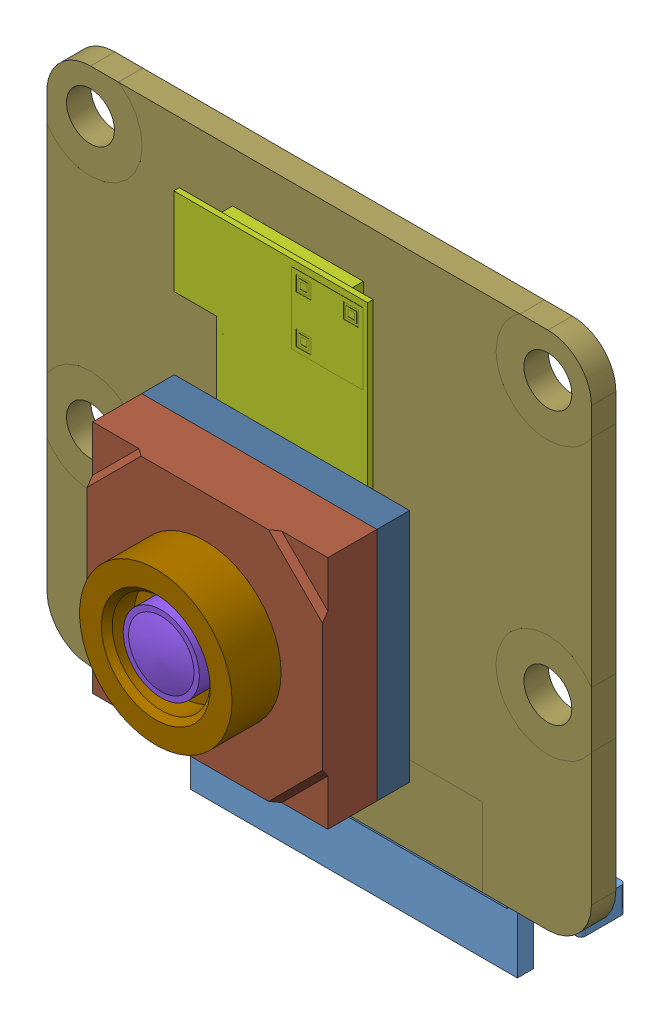
SolidWorks assembly AV_Comp_Mech_1_3_1_6_Pi_Cam, configuration Default. Lengths in mm.
Overall size (25 28.06 11.35).
16 component instances, 13 part files, 0 mates.
Components (placement in the parent):
- AV_Comp_Mech_1_3_1_6_Pi_Cam.step-1: AV_Comp_Mech_1_3_1_6_Pi_Cam.step [Default] at origin size (25 28.06 11.35)
  - Rear Components.step-1: Rear Components.step [Default] at origin size (20.8 26.49 2.7)
    - sfw15r3ste1lf.step-1: sfw15r3ste1lf.step [Default] at (-17.3 -10.562 -4.82) x (1 0 0) z (0 -1 0) size (20.8 2.7 9.5)
    - Rear Components-0.step-1: Rear Components-0.step [Default] at origin size (3 1.5 1)
    - Rear Components-1.step-1: Rear Components-1.step [Default] at origin size (5 3 1)
    - Rear Components-2.step-1: Rear Components-2.step [Default] at origin size (3 1.5 1)
    - Rear Components-3.step-1: Rear Components-3.step [Default] at origin size (3 1.5 1)
    - Rear Components-4.step-1: Rear Components-4.step [Default] at origin size (2 3 1)
  - Sony IMX708.step-1: Sony IMX708.step [Default] at origin size (10.83 18.1 7.53)
    - Sensor.step-1: Sensor.step [Default] at origin size (8.9 16.17 1.26)
    - Lens.step-1: Lens.step [Default] at origin size (3.5 3.5 6.28)
    - Ring.step-1: Ring.step [Default] at origin size (7 7 6.25)
    - Mount.step-1: Mount.step [Default] at origin size (10.8 10.8 1.5)
    - Housing.step-1: Housing.step [Default] at origin size (10.8 10.8 2.5)
  - Board.step-1: Board.step [Default] at origin size (25 23.86 1.12)
  - Camera Moudule 3.step-1: Camera Moudule 3.step [Default] at origin size (6.95 6.95 1.12)
